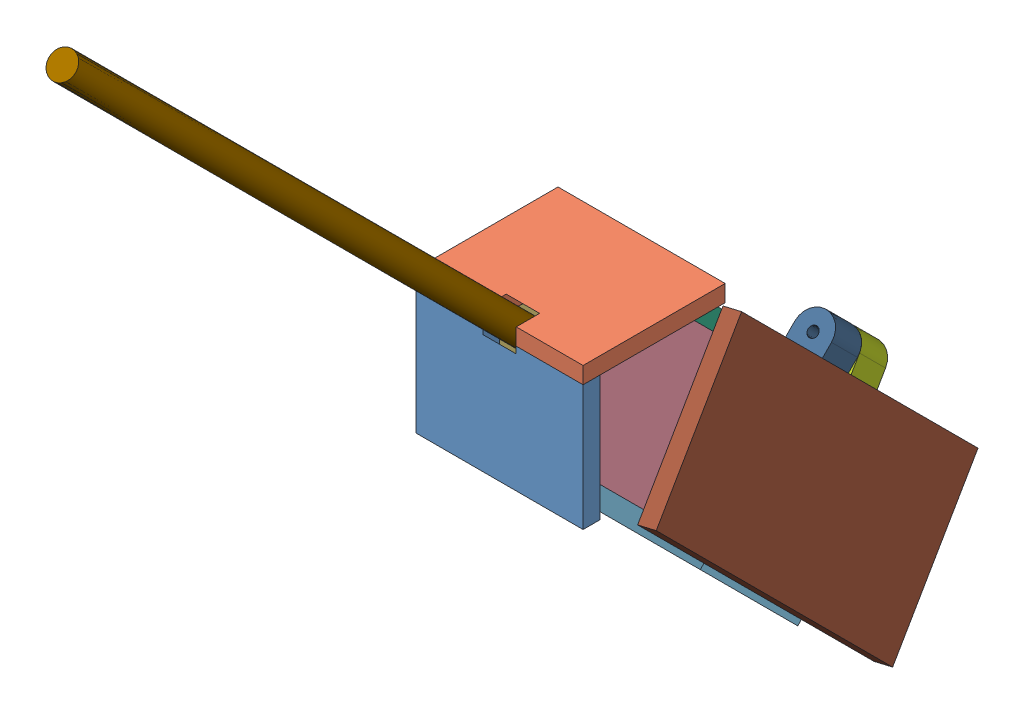
SolidWorks assembly AssemblaCabineDePlage(Vert), configuration Défaut. Lengths in mm.
Overall size (130.24 490.4 492.7).
11 component instances, 11 part files, 26 mates.
Components (placement in the parent):
- Pièce2-1: Pièce2 [Défaut] at (3.4185 -2.3604 95) size (100 75 10)
- Pièce3-vers2-1: Pièce3-vers2 [Défaut] at (3.4185 45.1396 62.5) x (1 0 0) z (0 -1 0) size (100 85 10)
- Pièce6-1: Pièce6 [Défaut] at (-36.5815 -0.2157 59.6447) x (0 -0.707107 0.707107) z (-1 0 0) size (80 100 10)
- Pièce7-1: Pièce7 [Défaut] at (43.4185 -20.9512 38.2695) x (0 0.707107 -0.707107) z (1 0 0) size (80 135 10)
- Pièce4-1: Pièce4 [Défaut] at (3.4185 -102.7462 27.8249) x (1 0 0) z (0 0.707107 -0.707107) size (100 210 10)
- Pièce5-1: Pièce5 [Défaut] at (3.4185 -39.1066 -35.8148) x (1 0 0) z (0 0.707107 -0.707107) size (100 210 10)
- Pièce10-5: Pièce10 [Défaut] at (64.4702 -89.2607 -33.7439) x (0.982877 0.130294 -0.130294) z (0 0.707107 0.707107) size (99 113.14 22)
- Pièce11-1: Pièce11 [Défaut] at (-11.5815 -141.6371 -81.7767) x (0 -0.707107 0.707107) z (0 0.707107 0.707107) size (80 70 10)
- Pièce1-1: Pièce1 [Défaut] at (3.4185 125.4912 185.3516) x (-0.216348 -0.69036 0.69036) z (-0.976316 0.152981 -0.152981) size (16 500 16)
- Pièce12-2: Pièce12 [Défaut] at (3.4185 -52.8952 -7.884) x (0 -0.707107 0.707107) z (0 -0.707107 -0.707107) size (112 100 22)
- Pièce8-3: Pièce8 [Défaut] at (74.4498 -68.0207 -13.9717) x (0.184263 -0.694999 0.694999) z (-0.982877 -0.130294 0.130294) size (100 200 10)
Mates (geometry in assembly coordinates):
- Coïncidente1: coincident anti-aligned: plane of Pièce2-1 through (-46.5815 35.1396 105) normal (0 1 0); plane of Pièce3-vers2-1 through (3.4185 35.1396 62.5) normal (0 -1 0)
- Coïncidente2: coincident aligned: line of Pièce2-1 through (-46.5815 35.1396 105) axis (1 0 0); line of Pièce3-vers2-1 through (13.4185 35.1396 105) axis (1 0 0)
- Coïncidente3: coincident anti-aligned: line of Pièce2-1 through (53.4185 35.1396 105) axis (0 0 -1); line of Pièce3-vers2-1 through (53.4185 35.1396 20) axis (0 0 1)
- Coïncidente5: coincident anti-aligned: plane of Pièce3-vers2-1 through (3.4185 35.1396 62.5) normal (0 -1 0); plane of Pièce6-1 through (-46.5815 35.1396 38.4315) normal (0 1 0)
- Coïncidente6: coincident anti-aligned: plane of Pièce2-1 through (3.4185 -2.3604 95) normal (0 0 -1); plane of Pièce6-1 through (-46.5815 35.1396 95) normal (0 0 1)
- Coïncidente7: coincident aligned: line of Pièce2-1 through (-46.5815 -39.8604 95) axis (0 1 0); line of Pièce6-1 through (-46.5815 -21.4289 95) axis (0 1 0)
- Coïncidente8: coincident anti-aligned: plane of Pièce3-vers2-1 through (3.4185 35.1396 62.5) normal (0 -1 0); plane of Pièce7-1 through (53.4185 35.1396 95) normal (0 1 0)
- Coïncidente9: coincident anti-aligned: plane of Pièce2-1 through (3.4185 -2.3604 95) normal (0 0 -1); plane of Pièce7-1 through (53.4185 -21.4289 95) normal (0 0 1)
- Coïncidente10: coincident aligned: line of Pièce2-1 through (53.4185 -39.8604 95) axis (0 1 0); line of Pièce7-1 through (53.4185 -21.4289 95) axis (0 1 0)
- Coïncidente12: coincident anti-aligned: plane of Pièce2-1 through (3.4185 -2.3604 95) normal (0 0 -1); plane of Pièce4-1 through (-46.5815 -21.4289 95) normal (0 0 1)
- Coïncidente13: coincident anti-aligned: plane of Pièce7-1 through (53.4185 -88.6041 27.8249) normal (0 -0.707107 0.707107); plane of Pièce4-1 through (3.4185 -95.6751 20.7538) normal (0 0.707107 -0.707107)
- Coïncidente14: coincident anti-aligned: line of Pièce7-1 through (53.4185 -88.6041 27.8249) axis (0 0.707107 0.707107); line of Pièce4-1 through (53.4185 -21.4289 95) axis (0 -0.707107 -0.707107)
- Coïncidente15: coincident anti-aligned: plane of Pièce3-vers2-1 through (3.4185 35.1396 62.5) normal (0 -1 0); plane of Pièce5-1 through (-46.5815 35.1396 38.4315) normal (0 1 0)
- Coïncidente16: coincident anti-aligned: plane of Pièce6-1 through (-46.5815 -7.2868 -3.9949) normal (0 0.707107 -0.707107); plane of Pièce5-1 through (3.4185 -39.1066 -35.8148) normal (0 -0.707107 0.707107)
- Coïncidente17: coincident anti-aligned: line of Pièce7-1 through (53.4185 35.1396 38.4315) axis (0 -0.707107 -0.707107); line of Pièce5-1 through (53.4185 -32.0355 -28.7437) axis (0 0.707107 0.707107)
- Coïncidente55: coincident anti-aligned: plane of Pièce5-1 through (3.4185 -39.1066 -35.8148) normal (0 -0.707107 0.707107); plane of Pièce11-1 through (-46.5815 -106.2817 -102.9899) normal (0 0.707107 -0.707107)
- Coïncidente56: coincident aligned: line of Pièce5-1 through (-46.5815 -113.3528 -110.061) axis (1 0 0); line of Pièce11-1 through (-46.5815 -113.3528 -110.061) axis (1 0 0)
- Coïncidente57: coincident aligned: line of Pièce5-1 through (-46.5815 -106.2817 -117.132) axis (0 -0.707107 0.707107); line of Pièce11-1 through (-46.5815 -113.3528 -110.061) axis (0 -0.707107 0.707107)
- Coïncidente58: coincident anti-aligned: plane of Pièce7-1 through (53.4185 -88.6041 27.8249) normal (0 -0.707107 -0.707107); plane of Pièce12-2 through (42.4185 -17.1863 -43.5929) normal (0 0.707107 0.707107)
- Coïncidente59: coincident anti-aligned: plane of Pièce4-1 through (3.4185 -95.6751 20.7538) normal (0 0.707107 -0.707107); plane of Pièce12-2 through (53.4185 -104.1604 12.2685) normal (0 -0.707107 0.707107)
- Coïncidente60: coincident anti-aligned: line of Pièce5-1 through (-46.5815 35.1396 38.4315) axis (0 -0.707107 -0.707107); line of Pièce12-2 through (-46.5815 -47.5919 -44.3) axis (0 0.707107 0.707107)
- Coïncidente63: coincident anti-aligned: circle of Pièce10-5; circle of Pièce12-2
- Coïncidente64: coincident anti-aligned: plane of Pièce10-5 through (64.4702 -73.7043 -18.1876) normal (0.982877 0.130294 -0.130294); plane of Pièce8-3 through (64.6211 -69.3237 -12.6688) normal (-0.982877 -0.130294 0.130294)
- Distance1: distance = 71 mm: line of Pièce10-5 through (72.025 -117.7557 -5.249) axis (-0.184263 0.694999 -0.694999); line of Pièce8-3 through (55.4079 -105.2844 -118.1294) axis (0.184263 -0.694999 0.694999)
- Distance7: distance = 11.8188 mm: line of Pièce8-3 through (55.4079 36.137 23.292) axis (0 -0.707107 -0.707107); line of Pièce10-5 through (53.2301 -31.3094 -60.5825) axis (0 -0.707107 -0.707107)
- Coaxiale1: concentric aligned: cylinder of Pièce1-1 through (3.4185 306.6561 366.5165) axis (0 0.707107 0.707107) radius 8; cylinder of Pièce12-2 through (3.4185 -75.8762 -16.0158) axis (0 0.707107 0.707107) radius 8
